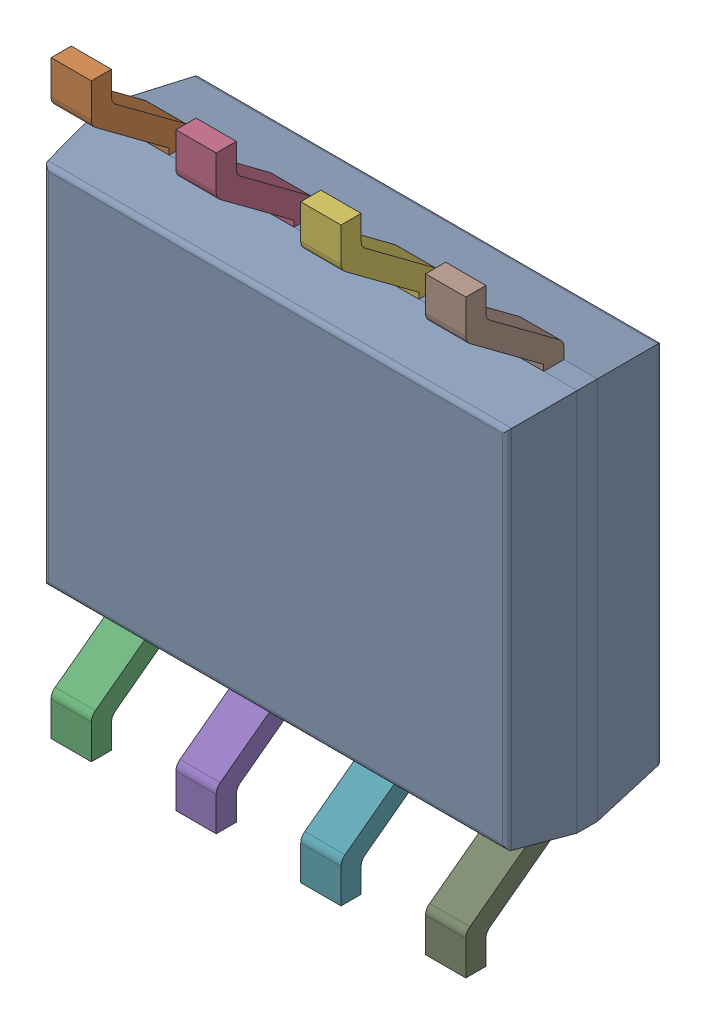
SolidWorks assembly IC4_3.step, configuration Default. Lengths in mm.
Overall size (4.9 6 1.75).
3 component instances, 2 part files, 0 mates.
Components (placement in the parent):
- 12042009920.step-1: 12042009920.step [Default] at (123.952 51.054 -1.0914) x (0 -1 0) z (0 0 -1) size (6 4.9 1.75)
  - Body_5.step-11: Body_5.step [Default] at origin size (3.9 4.9 1.57)
  - PinsArrayLR_3.step-11: PinsArrayLR_3.step [Default] at origin size (6 4.22 1)
